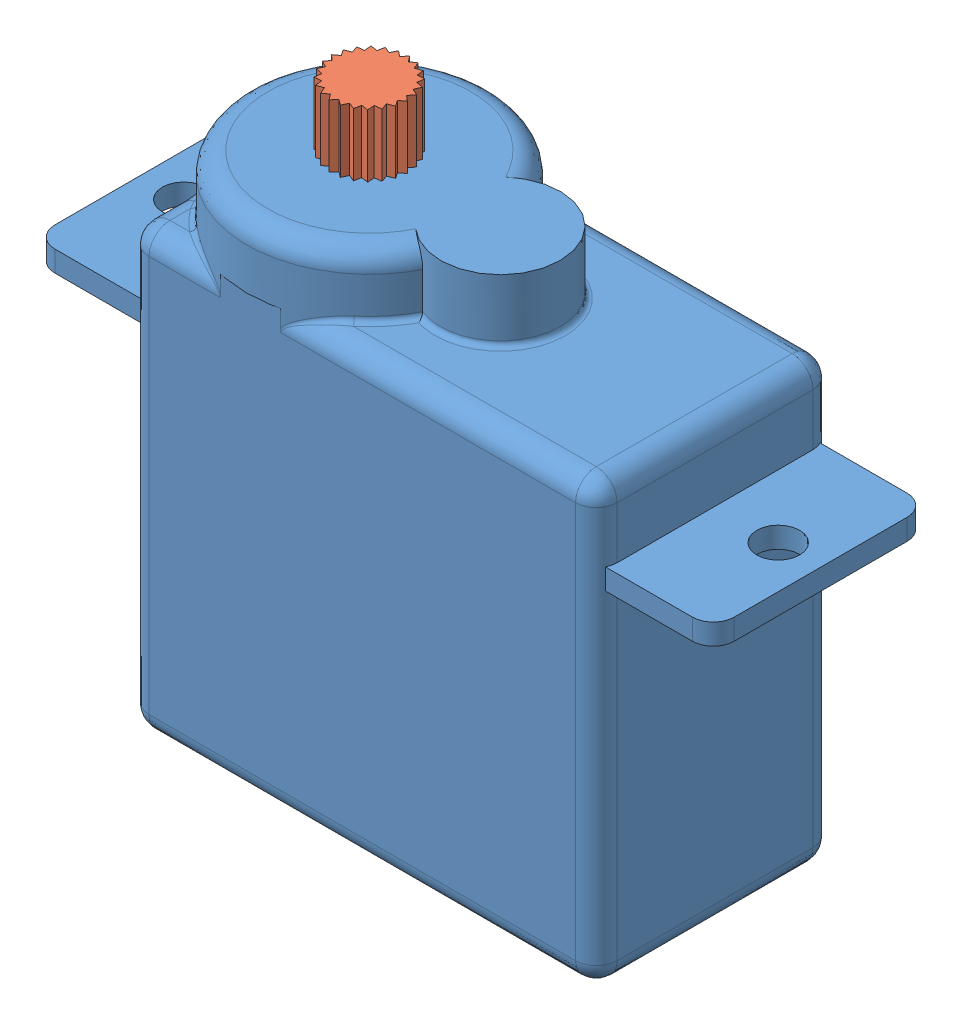
SolidWorks assembly HS-55_Servo, configuration Default. Lengths in mm.
Overall size (32.54 27 11.73).
2 component instances, 2 part files, 3 mates.
Components (placement in the parent):
- Hi-Tec_HS-55_Body-1: Hi-Tec_HS-55_Body [Default] at origin size (32.54 24.06 11.73)
- Hi-Tec_HS-55_Shaft-1: Hi-Tec_HS-55_Shaft [Default] at (0 3 0) x (0.999553 0 0.029907) z (-0.029907 0 0.999553) size (3.75 3 3.75)
Mates (geometry in assembly coordinates):
- Coincident1: coordinate: point of Hi-Tec_HS-55_Body-1; point of assembly
- Coincident2: coincident anti-aligned: plane of Hi-Tec_HS-55_Body-1 through (3.1369 0 0) normal (0 1 0); plane of Hi-Tec_HS-55_Shaft-1 through (0 0 0) normal (0 -1 0)
- Coincident4: coincident anti-aligned: line of Hi-Tec_HS-55_Shaft-1 through (0 3.15 0) axis (0 -1 0); line of assembly
